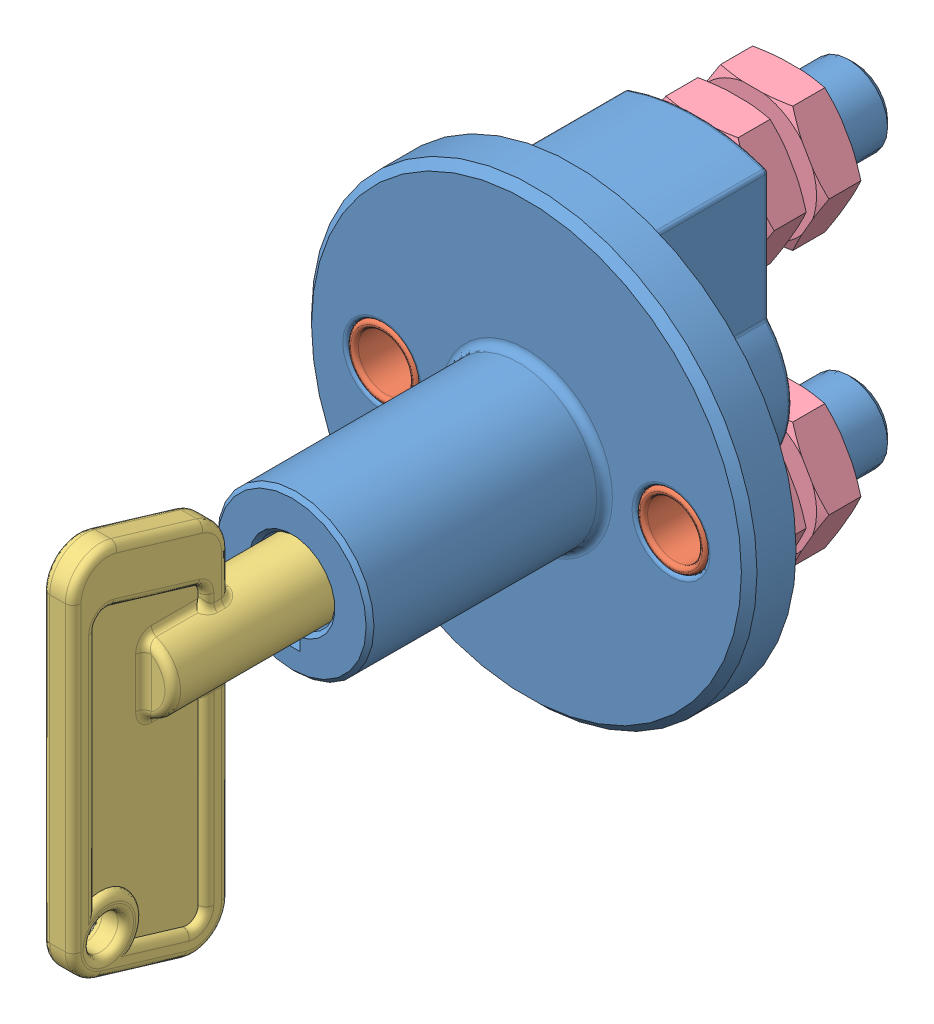
SolidWorks assembly PUTM-H-TS-BOX-Battery_Master_Switch, configuration Default. Lengths in mm.
Overall size (57 61.6 102).
8 component instances, 4 part files, 0 mates.
Components (placement in the parent):
- BMS Body-1: BMS Body [Default] at (-41.4967 6.5022 22.4798) size (57 57 72)
- BMS Insert-1: BMS Insert [Default] at (-5.0904 6.5022 22.4798) size (9 9 6)
- BMS Insert-2: BMS Insert [Default] at (-77.9031 6.5022 28.4798) x (-1 0 0) z (0 0 -1) size (9 9 6)
- BMS Key-1: BMS Key [Default] at (-43.4967 -14.8166 -10.0163) size (9.5 50.9 50)
- ISO 4035 M10 thin nut-1: ISO 4035 M10 thin nut [Default] at (-41.4967 24.0022 1.4798) size (18.48 16 5)
- ISO 4035 M10 thin nut-2: ISO 4035 M10 thin nut [Default] at (-41.4967 24.0022 -5.5202) size (18.48 16 5)
- ISO 4035 M10 thin nut-3: ISO 4035 M10 thin nut [Default] at (-41.4967 -10.9978 6.4798) x (1 0 0) z (0 0 -1) size (18.48 16 5)
- ISO 4035 M10 thin nut-4: ISO 4035 M10 thin nut [Default] at (-41.4967 -10.9978 -0.5202) x (1 0 0) z (0 0 -1) size (18.48 16 5)
